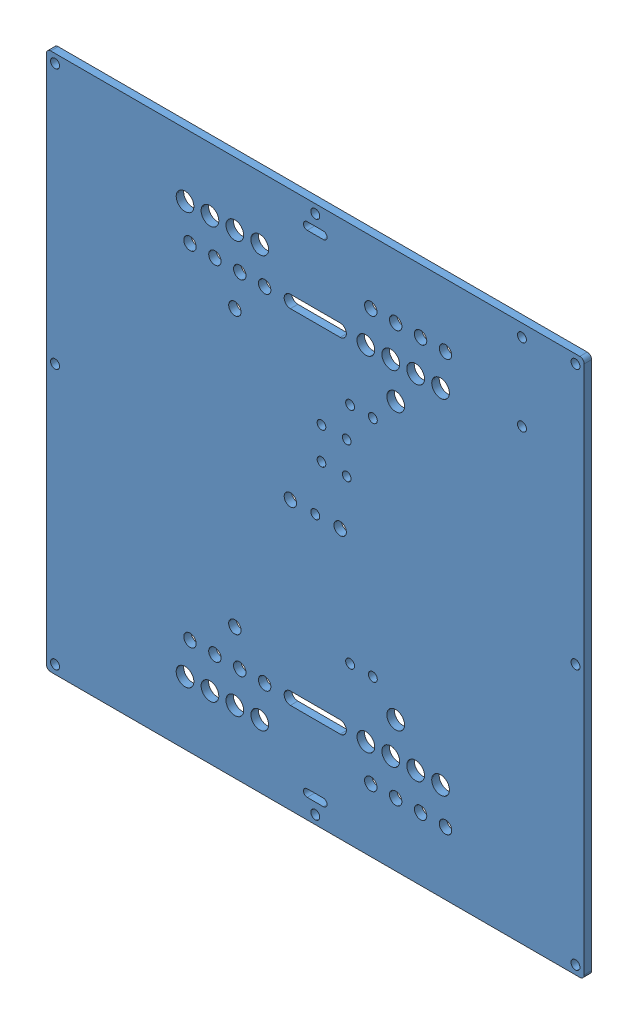
SolidWorks assembly Universal Build Plate with Delrin V-Wheels for 40mm V-Slot, configuration Default. Lengths in mm.
Overall size (216 216 3).
33 component instances, 7 part files, 7 mates.
Components (placement in the parent):
- V-Slot Universal Build Plate-1: V-Slot Universal Build Plate [Default] at (-53.2124 10.1898 21.1567) size (216 216 3)
- V-Slot Delrin Dual Wheel Assembly-1: V-Slot Delrin Dual Wheel Assembly [Default] at (-87.7089 66.118 18.8913) size (23.89 23.89 27.2) (hidden)
  - Delrin Dual V-Wheel-1: Delrin Dual V-Wheel [Default] at (4.1766 13.0717 -11.0846) size (23.89 23.89 10.23)
  - Precision Ball Bearing-1: Precision Ball Bearing [Default] at (4.1766 13.0717 -8.0846) x (0 0 -1) z (1 0 0) size (5 16 16)
  - Precision Ball Bearing-2: Precision Ball Bearing [Default] at (4.1766 13.0717 -14.0846) x (0 0 -1) z (1 0 0) size (5 16 16)
  - 5mm Precision Washer-1: 5mm Precision Washer [Default] at (4.1766 13.0717 -11.5846) x (0 0 1) z (-1 0 0) size (1 10 10)
  - .25 Inch Aluminum Spacer-1: .25 Inch Aluminum Spacer [Default] at (4.1766 13.0717 0.7654) x (0 0 -1) z (1 0 0) size (6.35 8 8)
  - 5mm Low Profile Socket Head Screw - Multiple Lengths-1: 5mm Low Profile Socket Head Screw - Multiple Lengths [Default] at (4.1766 13.0717 5.5154) x (0 0 -1) z (1 0 0) size (27.2 9.5 9.5)
  - Nylon Insert Hex Locknut 5mm-1: Nylon Insert Hex Locknut 5mm [Default] at (4.1766 13.0717 -16.5846) x (-0.923728 -0.383049 0) z (0 0 -1) size (7.68 8.82 4.5)
- V-Slot Delrin Dual Wheel Assembly-2: V-Slot Delrin Dual Wheel Assembly [Default] at (-87.7089 -71.882 18.8913) size (23.89 23.89 27.2) (hidden)
  - Delrin Dual V-Wheel-1: Delrin Dual V-Wheel [Default] at (4.1766 13.0717 -11.0846) size (23.89 23.89 10.23)
  - Precision Ball Bearing-1: Precision Ball Bearing [Default] at (4.1766 13.0717 -8.0846) x (0 0 -1) z (1 0 0) size (5 16 16)
  - Precision Ball Bearing-2: Precision Ball Bearing [Default] at (4.1766 13.0717 -14.0846) x (0 0 -1) z (1 0 0) size (5 16 16)
  - 5mm Precision Washer-1: 5mm Precision Washer [Default] at (4.1766 13.0717 -11.5846) x (0 0 1) z (-1 0 0) size (1 10 10)
  - .25 Inch Aluminum Spacer-1: .25 Inch Aluminum Spacer [Default] at (4.1766 13.0717 0.7654) x (0 0 -1) z (1 0 0) size (6.35 8 8)
  - 5mm Low Profile Socket Head Screw - Multiple Lengths-1: 5mm Low Profile Socket Head Screw - Multiple Lengths [Default] at (4.1766 13.0717 5.5154) x (0 0 -1) z (1 0 0) size (27.2 9.5 9.5)
  - Nylon Insert Hex Locknut 5mm-1: Nylon Insert Hex Locknut 5mm [Default] at (4.1766 13.0717 -16.5846) x (-0.923728 -0.383049 0) z (0 0 -1) size (7.68 8.82 4.5)
- V-Slot Delrin Dual Wheel Assembly-3: V-Slot Delrin Dual Wheel Assembly [Default] at (-15.3542 67.7229 18.8913) x (0.62878 0.777583 0) z (0 0 1) size (23.89 23.89 27.2) (hidden)
  - Delrin Dual V-Wheel-1: Delrin Dual V-Wheel [Default] at (4.1766 13.0717 -11.0846) size (23.89 23.89 10.23)
  - Precision Ball Bearing-1: Precision Ball Bearing [Default] at (4.1766 13.0717 -8.0846) x (0 0 -1) z (1 0 0) size (5 16 16)
  - Precision Ball Bearing-2: Precision Ball Bearing [Default] at (4.1766 13.0717 -14.0846) x (0 0 -1) z (1 0 0) size (5 16 16)
  - 5mm Precision Washer-1: 5mm Precision Washer [Default] at (4.1766 13.0717 -11.5846) x (0 0 1) z (-1 0 0) size (1 10 10)
  - .25 Inch Aluminum Spacer-1: .25 Inch Aluminum Spacer [Default] at (4.1766 13.0717 0.7654) x (0 0 -1) z (1 0 0) size (6.35 8 8)
  - 5mm Low Profile Socket Head Screw - Multiple Lengths-1: 5mm Low Profile Socket Head Screw - Multiple Lengths [Default] at (4.1766 13.0717 5.5154) x (0 0 -1) z (1 0 0) size (27.2 9.5 9.5)
  - Nylon Insert Hex Locknut 5mm-1: Nylon Insert Hex Locknut 5mm [Default] at (4.1766 13.0717 -16.5846) x (-0.923728 -0.383049 0) z (0 0 -1) size (7.68 8.82 4.5)
- V-Slot Delrin Dual Wheel Assembly-4: V-Slot Delrin Dual Wheel Assembly [Default] at (-27.0689 -71.882 18.8913) size (23.89 23.89 27.2) (hidden)
  - Delrin Dual V-Wheel-1: Delrin Dual V-Wheel [Default] at (4.1766 13.0717 -11.0846) size (23.89 23.89 10.23)
  - Precision Ball Bearing-1: Precision Ball Bearing [Default] at (4.1766 13.0717 -8.0846) x (0 0 -1) z (1 0 0) size (5 16 16)
  - Precision Ball Bearing-2: Precision Ball Bearing [Default] at (4.1766 13.0717 -14.0846) x (0 0 -1) z (1 0 0) size (5 16 16)
  - 5mm Precision Washer-1: 5mm Precision Washer [Default] at (4.1766 13.0717 -11.5846) x (0 0 1) z (-1 0 0) size (1 10 10)
  - .25 Inch Aluminum Spacer-1: .25 Inch Aluminum Spacer [Default] at (4.1766 13.0717 0.7654) x (0 0 -1) z (1 0 0) size (6.35 8 8)
  - 5mm Low Profile Socket Head Screw - Multiple Lengths-1: 5mm Low Profile Socket Head Screw - Multiple Lengths [Default] at (4.1766 13.0717 5.5154) x (0 0 -1) z (1 0 0) size (27.2 9.5 9.5)
  - Nylon Insert Hex Locknut 5mm-1: Nylon Insert Hex Locknut 5mm [Default] at (4.1766 13.0717 -16.5846) x (-0.923728 -0.383049 0) z (0 0 -1) size (7.68 8.82 4.5)
Mates (geometry in assembly coordinates):
- Coincident1: coincident: plane of V-Slot Universal Build Plate-1 through (-159.4624 -96.0602 22.6567) normal (0 0 1); plane of V-Slot Delrin Dual Wheel Assembly-3/5mm Low Profile Socket Head Screw - Multiple Lengths-1 through (84.7108 40.3829 22.6567) normal (0 0 -1)
- Coincident2: coincident anti-aligned: plane of V-Slot Universal Build Plate-1 through (-159.4624 -96.0602 22.6567) normal (0 0 1); plane of V-Slot Delrin Dual Wheel Assembly-4/5mm Low Profile Socket Head Screw - Multiple Lengths-1 through (-22.8924 -56.3102 22.6567) normal (0 0 -1)
- Coincident3: coincident anti-aligned: plane of V-Slot Universal Build Plate-1 through (-159.4624 -96.0602 22.6567) normal (0 0 1); plane of V-Slot Delrin Dual Wheel Assembly-1/5mm Low Profile Socket Head Screw - Multiple Lengths-1 through (-83.5324 81.6898 22.6567) normal (0 0 -1)
- Coincident4: coincident anti-aligned: plane of V-Slot Universal Build Plate-1 through (-159.4624 -96.0602 22.6567) normal (0 0 1); plane of V-Slot Delrin Dual Wheel Assembly-2/5mm Low Profile Socket Head Screw - Multiple Lengths-1 through (-83.5324 -56.3102 22.6567) normal (0 0 -1)
- Concentric3: concentric anti-aligned: cylinder of V-Slot Universal Build Plate-1 through (-83.5324 -58.8102 22.6567) axis (0 0 -1) radius 2.5; cylinder of V-Slot Delrin Dual Wheel Assembly-2/.25 Inch Aluminum Spacer-1 through (-83.5324 -58.8102 13.3067) axis (0 0 1) radius 4
- Concentric4: concentric anti-aligned: cylinder of V-Slot Universal Build Plate-1 through (-83.5324 79.1898 22.6567) axis (0 0 -1) radius 2.5; cylinder of V-Slot Delrin Dual Wheel Assembly-1/.25 Inch Aluminum Spacer-1 through (-83.5324 79.1898 13.3067) axis (0 0 1) radius 4
- Concentric5: concentric anti-aligned: cylinder of V-Slot Universal Build Plate-1 through (-22.8924 79.1898 22.6567) axis (0 0 -1) radius 3.57; cylinder of V-Slot Delrin Dual Wheel Assembly-3/.25 Inch Aluminum Spacer-1 through (-22.8924 79.1898 13.3067) axis (0 0 1) radius 4
